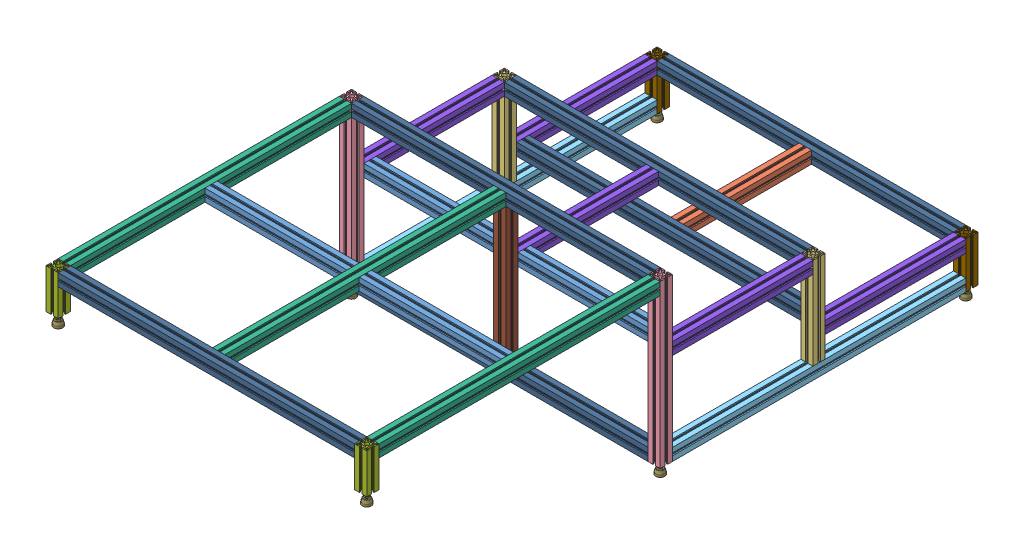
SolidWorks assembly Pd3 00-1-00, configuration Domyślna. Lengths in mm.
Overall size (1050 567 2000).
36 component instances, 12 part files, 10 mates.
Components (placement in the parent):
- Profil 40x40x465-3: Profil 40x40x465 [Default] at (-940 -230 -40) x (0 0 -1) z (1 0 0) size (40 40 465)
- Profil 40x40x465-4: Profil 40x40x465 [Default] at (-435 -230 -40) x (0 0 -1) z (1 0 0) size (40 40 465)
- LustroProfil 40x40x420-1: LustroProfil 40x40x420 [Default] at (-475 -420 -580) size (40 40 420)
- Profil 40x40x300-1: Profil 40x40x300 [Default] at (-980 -190 -540) x (1 0 0) z (0 -1 0) size (40 40 300)
- Profil 40x40x530-1: Profil 40x40x530 [Default] at (-980 -530 0) x (1 0 0) z (0 1 0) size (40 40 530)
- Profil 40x40x960-1: Profil 40x40x960 [Default] at (-980 -530 -1000) size (40 40 960)
- Profil 40x40x920-19: Profil 40x40x920 [Default] at (30 -40 0) size (40 40 920)
- Profil 40x40x130-5: Profil 40x40x130 [Default] at (30 -130 960) x (1 0 0) z (0 1 0) size (40 40 130)
- Profil 40x40x530-3: Profil 40x40x530 [Default] at (30 -530 0) x (1 0 0) z (0 1 0) size (40 40 530)
- Profil 40x40x460-10: Profil 40x40x460 [Default] at (30 -230 -500) size (40 40 460)
- Profil 40x40x960-3: Profil 40x40x960 [Default] at (30 -530 -1000) size (40 40 960)
- Profil 40x40x150-3: Profil 40x40x150 [Default] at (30 -380 -1040) x (1 0 0) z (0 -1 0) size (40 40 150)
- Profil 40x40x300-3: Profil 40x40x300 [Default] at (30 -190 -540) x (1 0 0) z (0 -1 0) size (40 40 300)
- Profil 40x40x460-11: Profil 40x40x460 [Default] at (30 -420 -1000) size (40 40 460)
- Profil 40x40x970-1: Profil 40x40x970 [Default] at (-940 -40 960) x (0 0 -1) z (1 0 0) size (40 40 970)
- Profil 40x40x970-2: Profil 40x40x970 [Default] at (-940 -40 0) x (0 0 -1) z (1 0 0) size (40 40 970)
- Profil 40x40x970-3: Profil 40x40x970 [Default] at (-940 -530 0) x (0 0 -1) z (1 0 0) size (40 40 970)
- Profil 40x40x970-4: Profil 40x40x970 [Default] at (-940 -230 -500) x (0 0 -1) z (1 0 0) size (40 40 970)
- Profil 40x40x970-6: Profil 40x40x970 [Default] at (-940 -420 -540) x (0 0 -1) z (1 0 0) size (40 40 970)
- Profil 40x40x970-7: Profil 40x40x970 [Default] at (-940 -420 -1000) x (0 0 -1) z (1 0 0) size (40 40 970)
- Profil 40x40x465-1: Profil 40x40x465 [Default] at (30 -40 440) x (0 0 1) z (-1 0 0) size (40 40 465)
- Profil 40x40x465-2: Profil 40x40x465 [Default] at (-475 -40 440) x (0 0 1) z (-1 0 0) size (40 40 465)
- Profil 40x40x920-13: Profil 40x40x920 [Default] at (-980 -40 0) size (40 40 920)
- Profil 40x40x130-3: Profil 40x40x130 [Default] at (-980 -130 960) x (1 0 0) z (0 1 0) size (40 40 130)
- Profil 40x40x920-17: Profil 40x40x920 [Default] at (-475 -40 0) size (40 40 920)
- Profil 40x40x150-1: Profil 40x40x150 [Default] at (-980 -380 -1040) x (1 0 0) z (0 -1 0) size (40 40 150)
- Profil 40x40x450-2: Profil 40x40x450 [Default] at (-475 -490 0) x (1 0 0) z (0 1 0) size (40 40 450)
- Profil 40x40x460-3: Profil 40x40x460 [Default] at (-980 -420 -1000) size (40 40 460)
- Profil 40x40x460-4: Profil 40x40x460 [Default] at (-980 -230 -500) size (40 40 460)
- Profil 40x40x460-9: Profil 40x40x460 [Default] at (-475 -230 -500) size (40 40 460)
- b43-10-6: b43-10 [Domyślna] at (-960 -565 -1020) size (29 77 29)
- b43-10-9: b43-10 [Domyślna] at (-960 -565 -20) size (29 77 29)
- b43-10-14: b43-10 [Domyślna] at (-960 -169 940) x (-0.989874 0 -0.141949) z (0.141949 0 -0.989874) size (29 77 29)
- b43-10-15: b43-10 [Domyślna] at (50 -565 -20) size (29 77 29)
- b43-10-16: b43-10 [Domyślna] at (50 -565 -1020) size (29 77 29)
- b43-10-17: b43-10 [Domyślna] at (50 -169 940) x (-0.989874 0 -0.141949) z (0.141949 0 -0.989874) size (29 77 29)
Mates (geometry in assembly coordinates):
- Wspólnie5: coincident anti-aligned: plane of Profil 40x40x300-3 through (46 -189 -540) normal (0 0 -1); plane of Profil 40x40x970-6 through (-941 -396 -540) normal (0 0 1)
- Wspólnie6: coincident aligned: plane of Profil 40x40x465-3 through (-941 -190 -64) normal (0 1 0); plane of Profil 40x40x465-4 through (-436 -190 -64) normal (0 1 0)
- Wspólnie7: coincident aligned: plane of Profil 40x40x465-3 through (-941 -190 -80) normal (0 0 -1); plane of Profil 40x40x465-4 through (-436 -190 -80) normal (0 0 -1)
- Wspólnie8: coincident aligned: plane of Profil 40x40x460-4 through (-956 -190 -501) normal (0 1 0); plane of Profil 40x40x465-4 through (-436 -190 -64) normal (0 1 0)
- Wspólnie9: coincident anti-aligned: plane of Profil 40x40x530-1 through (-956 -531 -40) normal (0 0 -1); plane of Profil 40x40x465-3 through (-941 -206 -40) normal (0 0 1)
- Wspólnie10: coincident anti-aligned: plane of Profil 40x40x460-4 through (-940 -190 -501) normal (1 0 0); plane of Profil 40x40x465-3 through (-940 -190 -35) normal (-1 0 0)
- Wspólnie11: coincident anti-aligned: plane of Profil 40x40x460-9 through (-435 -190 -501) normal (1 0 0); plane of Profil 40x40x465-4 through (-435 -190 -35) normal (-1 0 0)
- Wspólnie15: coincident aligned: plane of Profil 40x40x970-6 through (-941 -380 -564) normal (0 1 0); plane of LustroProfil 40x40x420-1 through (-451 -380 -579) normal (0 1 0)
- Wspólnie16: coincident aligned: plane of Profil 40x40x460-9 through (-435 -190 -501) normal (1 0 0); plane of LustroProfil 40x40x420-1 through (-435 -380 -579) normal (1 0 0)
- Wspólnie17: coincident anti-aligned: plane of Profil 40x40x970-6 through (-941 -380 -580) normal (0 0 -1); plane of LustroProfil 40x40x420-1 through (-480 -380 -580) normal (0 0 1)
